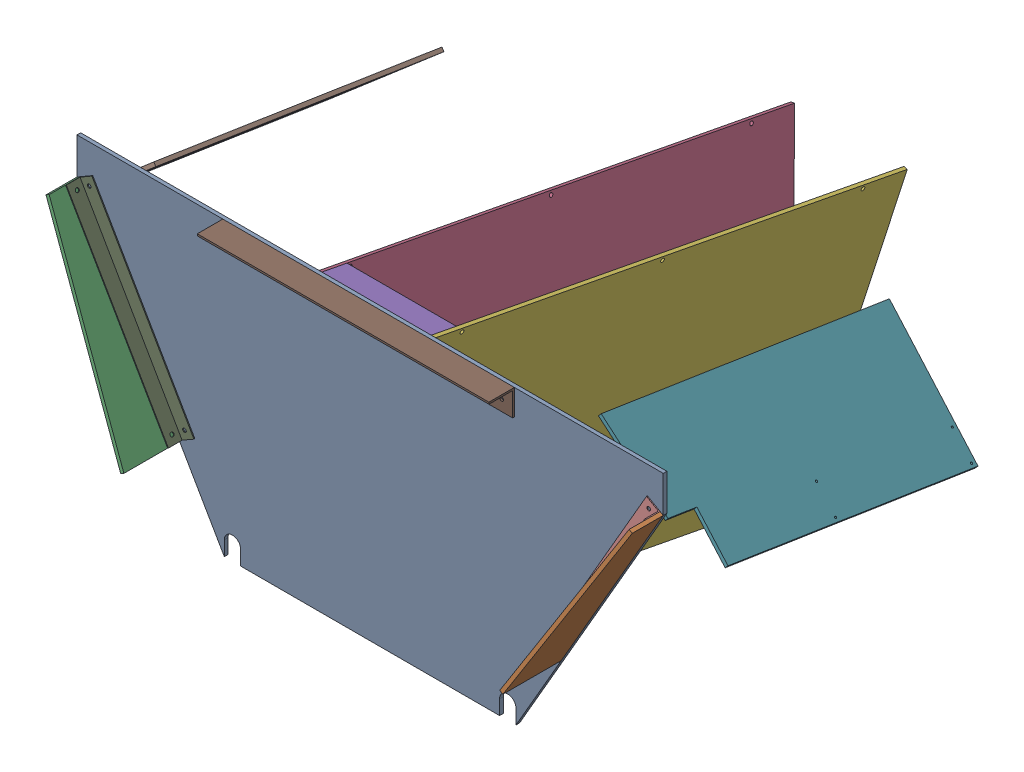
SolidWorks assembly GE-16112_ASM, configuration Default. Lengths in mm.
Overall size (1127.07 666.61 931.34).
11 component instances, 7 part files, 0 mates.
Components (placement in the parent):
- GE-16113-1: GE-16113 [Default] at origin size (1021.26 508 6.35)
- GE-16114-1: GE-16114 [Default] at (759.1329 447.675 6.35) x (0.866025 -0.5 0) z (0.5 0.866025 0) size (6.35 101.6 355.6)
- GE-16114-2: GE-16114 [Default] at (-256.6322 444.5 6.35) x (0.866025 0.5 0) z (-0.5 0.866025 0) size (6.35 101.6 355.6)
- GE-16115-1: GE-16115 [Default] at (163.6378 351.1437 -823.3926) x (0.176771 -0.966864 0.184188) z (-0.984252 -0.173648 0.03308) size (508 838.2 6.35)
- GE-16116-1: GE-16116 [Default] at (163.6378 456.0171 -35.3466) x (1 0 0) z (0 0.187135 0.982334) size (190.5 44.45 44.45)
- GE-16115-2: GE-16115 [Default] at (360.3329 349.7549 -823.1254) x (-0.185667 -0.965198 0.184177) z (-0.982613 0.182387 -0.034745) size (508 838.2 6.35)
- GE-16117-1: GE-16117 [Default] at (638.1063 525.4846 -12.1076) x (0.756757 -0.646017 0.099905) z (0.653697 0.747867 -0.115656) size (234.95 508 6.35)
- GE-16117-2: GE-16117 [Default] at (-128.0447 520.0211 -2.267) x (-0.761876 -0.640114 0.098992) z (0.647723 -0.752926 0.116438) size (234.95 508 6.35)
- GE-16118-1: GE-16118 [Default] at (-251.1329 447.675 6.35) x (0.5 -0.866025 0) z (0 0 1) size (355.6 25.4 25.4)
- GE-16118-2: GE-16118 [Default] at (581.3329 139.7164 6.35) x (0.5 0.866025 0) z (0 0 1) size (355.6 25.4 25.4)
- GE-16119-1: GE-16119 [Default] at (505.3678 508 50.8) x (-1 0 0) z (0 -1 0) size (508 44.45 44.45)
